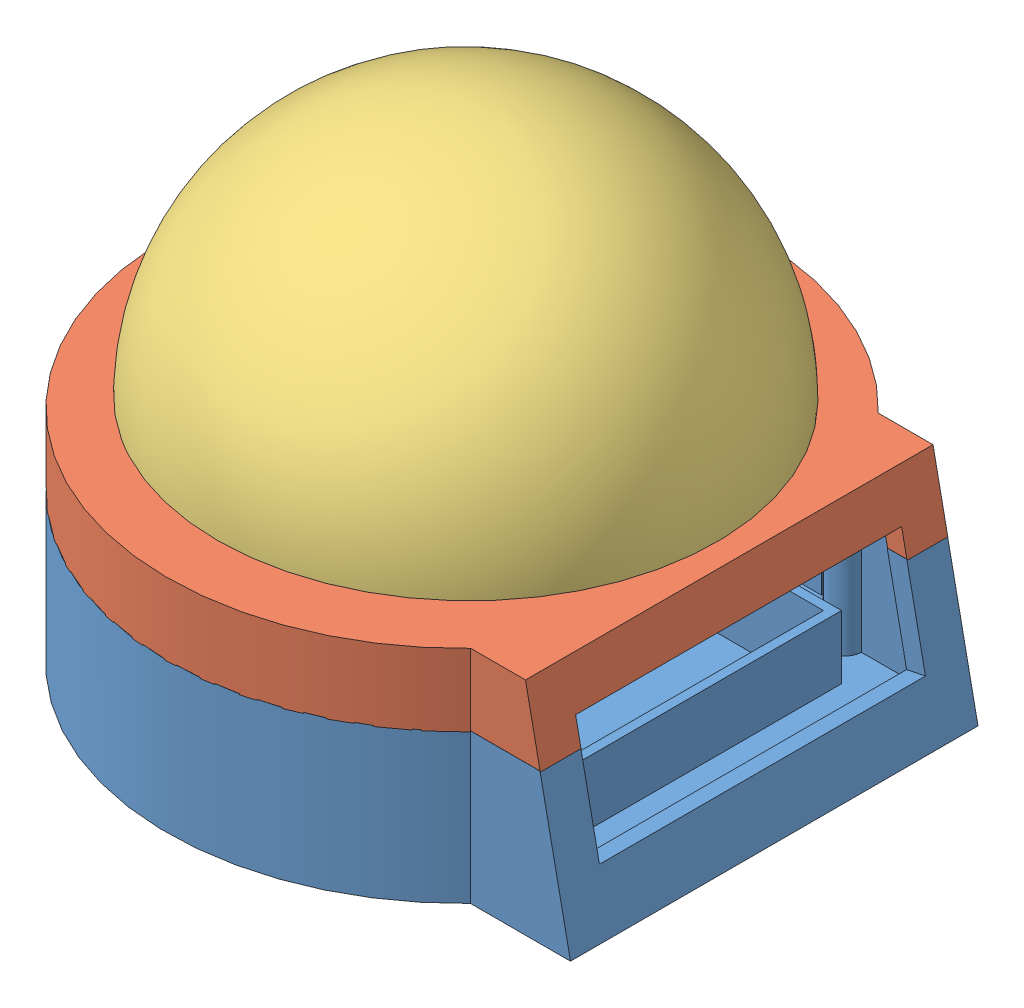
SolidWorks assembly ButtonAssembly, configuration Default. Lengths in mm.
Overall size (150.13 110.88 150.53).
3 component instances, 3 part files, 0 mates.
Components (placement in the parent):
- ButtonHousing2-1: ButtonHousing2 [Default] at (43.1139 62.0296 111.8664) size (134 38 130)
- ButtonHousingTop2-2: ButtonHousingTop2 [Default] at (43.1552 94.8282 111.842) size (127.27 16 130)
- ButtonTop2-1: ButtonTop2 [Default] at (43.2579 112.334 111.1522) x (0.86993 0.001804 0.493171) z (-0.493167 0.008704 0.869891) size (110 70 110)
